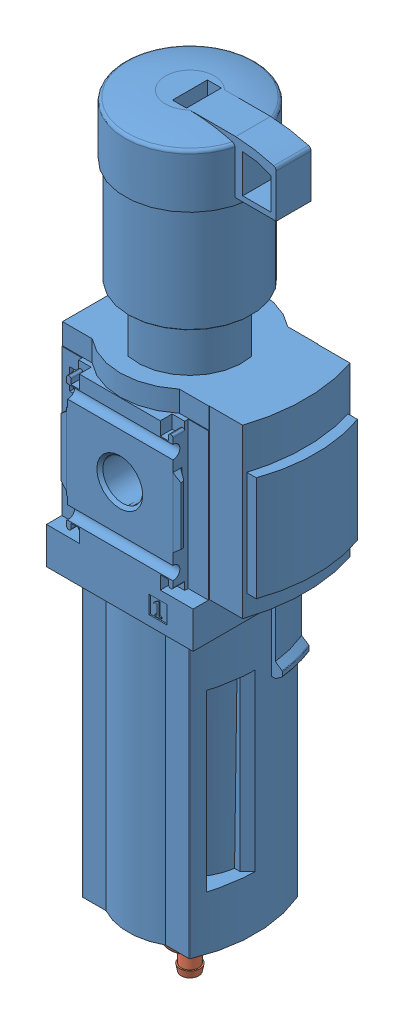
SolidWorks assembly 529156 MS4-LFR-1_4-D7-ERM-AS, configuration Default. Lengths in mm.
Overall size (57 218.5 40.2).
3 component instances, 3 part files, 0 mates.
Components (placement in the parent):
- 526489 MS4-LFR-1_4-D7-E-R-M-AS-0D-1: 526489 MS4-LFR-1_4-D7-E-R-M-AS-0D [Default] at origin size (57 201.54 40.2)
- 526489 MS4-LFR-M-1: 526489 MS4-LFR-M [Default] at (0 -113.6 0) x (-1 0 0) z (0 0 -1) size (12 17.7 12)
- 645204 MS4-1: 645204 MS4 [Default] at (-19 0 0) x (0 0 -1) z (-1 0 0) size (30.7 37.5 5.5)
